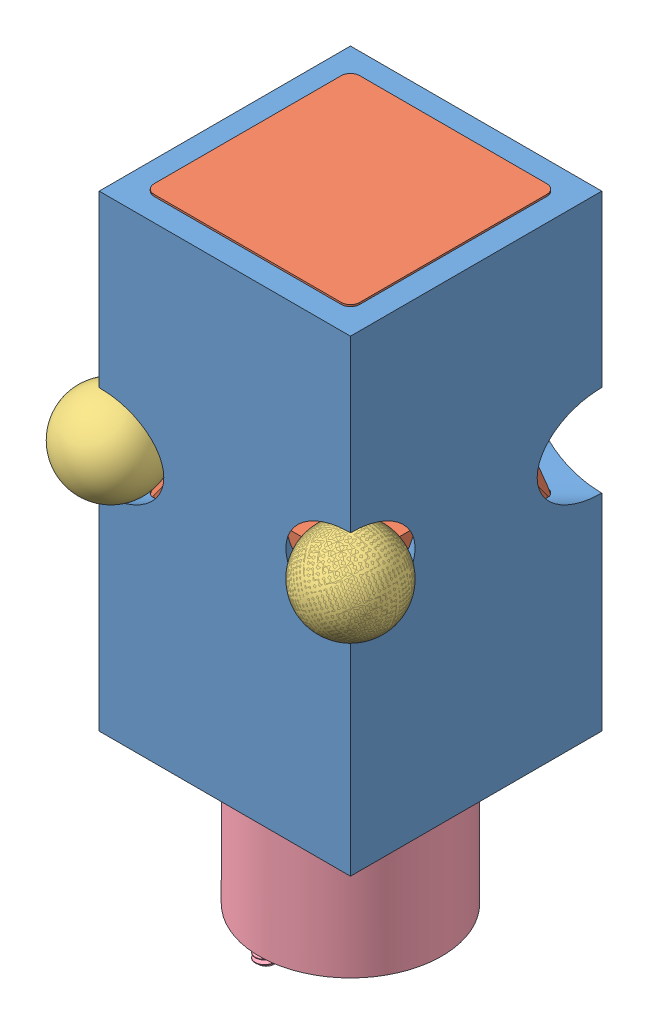
SolidWorks assembly Thesis3_assy, configuration Default. Lengths in mm.
Overall size (50.61 92.56 49.89).
7 component instances, 4 part files, 12 mates.
Components (placement in the parent):
- Thesis3_housing-1: Thesis3_housing [Default] at (20.4734 22.7723 59.4666) size (34.92 65 34.92)
- Thesis3_plunger-1: Thesis3_plunger [Default] at (20.4734 30.8707 59.4666) size (28.57 57.15 28.57)
- ball_bearing_.5-1: ball_bearing_.5 [Default] at (3.8205 57.7723 76.1195) x (0.258865 -0.640545 -0.722973) z (0.963308 0.11626 0.241912) size (12.7 12.7 12.7)
- ball_bearing_.5-2: ball_bearing_.5 [Default] at (37.1263 57.7723 76.1195) x (0.533838 -0.804766 0.259554) z (-0.84385 -0.487363 0.224486) size (12.7 12.7 12.7)
- ball_bearing_.5-3: ball_bearing_.5 [Default] at (37.1263 57.7723 76.1195) size (12.7 12.7 12.7)
- ball_bearing_.5-4: ball_bearing_.5 [Default] at (3.8205 57.7723 42.8137) size (12.7 12.7 12.7)
- 6873K110_COMPACT LINEAR SOLENOID-1: 6873K110_COMPACT LINEAR SOLENOID [6873K11] at (20.4734 2.0417 59.4666) x (-0.770252 0 -0.637739) z (0 -1 0) size (25.4 25.4 45.18)
Mates (geometry in assembly coordinates):
- Coincident1: coincident: plane of Thesis3_housing-1 through (20.4734 22.7723 59.4666) normal (0 0 1); plane of Thesis3_plunger-1 through (20.4734 30.8707 59.4666) normal (0 0 1)
- Coincident2: coincident: plane of Thesis3_housing-1 through (20.4734 22.7723 59.4666) normal (1 0 0); plane of Thesis3_plunger-1 through (20.4734 30.8707 59.4666) normal (1 0 0)
- Concentric1: concentric: cylinder of Thesis3_housing-1 through (3.0109 57.7723 42.0041) axis (0.707107 0 0.707107) radius 6.35; sphere of ball_bearing_.5-2
- Tangent5: tangent: sphere of ball_bearing_.5-2; cone of Thesis3_plunger-1 through (20.4734 49.9207 59.4666) axis (0 1 0)
- Tangent6: tangent: cone of Thesis3_plunger-1 through (20.4734 49.9207 59.4666) axis (0 1 0); sphere of ball_bearing_.5-3
- Concentric2: concentric: cylinder of Thesis3_housing-1 through (3.0109 57.7723 42.0041) axis (0.707107 0 0.707107) radius 6.35; sphere of ball_bearing_.5-3
- Concentric3: concentric: cylinder of Thesis3_housing-1 through (37.9359 57.7723 42.0041) axis (-0.707107 0 0.707107) radius 6.35; sphere of ball_bearing_.5-1
- Tangent10: tangent: cone of Thesis3_plunger-1 through (20.4734 49.9207 59.4666) axis (0 1 0); sphere of ball_bearing_.5-1
- Concentric4: concentric: cylinder of Thesis3_housing-1 through (3.0109 57.7723 42.0041) axis (0.707107 0 0.707107) radius 6.35; sphere of ball_bearing_.5-4
- Tangent12: tangent: cone of Thesis3_plunger-1 through (20.4734 49.9207 59.4666) axis (0 1 0); sphere of ball_bearing_.5-4
- Concentric5: concentric: cylinder of Thesis3_plunger-1 through (20.4734 83.3707 59.4666) axis (0 1 0) radius 8.7756; cylinder of 6873K110_COMPACT LINEAR SOLENOID-1 through (20.4734 18.8057 59.4666) axis (0 1 0) radius 12.7
- Distance1: distance = 9.525 mm: plane of Thesis3_plunger-1 through (20.4734 30.8707 59.4666) normal (0 -1 0); plane of 6873K110_COMPACT LINEAR SOLENOID-1 through (20.4734 40.3957 59.4666) normal (0 1 0)
